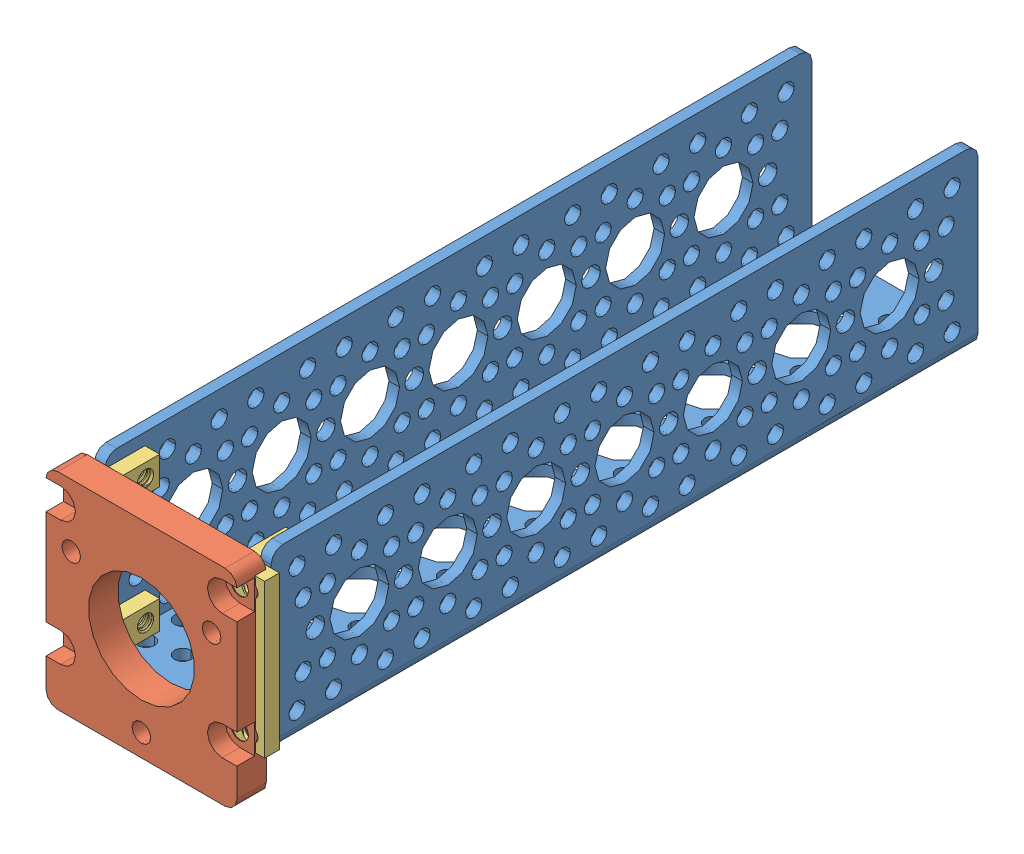
SolidWorks assembly Assem1, configuration Default. Lengths in mm.
Overall size (43.16 44.82 160.18).
4 component instances, 3 part files, 8 mates.
Components (placement in the parent):
- 6in Uchannel-1: 6in Uchannel [Default] at (-60.9804 -7.0848 -62.2029) size (38.1 38.1 152.4)
- L3v1 SlipRingBlock-1: L3v1 SlipRingBlock [Default] at (-43.0546 8.4219 91.6278) x (1 0 0) z (0 -1 0) size (41.15 6.35 44.45)
- J2v2 Angle Bracket 585508-1: J2v2 Angle Bracket 585508 [Default] at (-24.4044 11.9652 90.8328) x (0 1 0) z (1 0 0) size (33.02 12.43 7.88)
- J2v2 Angle Bracket 585508-2: J2v2 Angle Bracket 585508 [Default] at (-59.4564 11.9652 90.8328) x (0 -1 0) z (-1 0 0) size (33.02 12.43 7.88)
Mates (geometry in assembly coordinates):
- Coincident1: coincident anti-aligned: plane of 6in Uchannel-1 through (-25.1664 -4.7988 90.1971) normal (-1 0 0); plane of J2v2 Angle Bracket 585508-1 through (-25.1664 22.3945 81.5771) normal (1 0 0)
- Parallel1: parallel anti-aligned: plane of 6in Uchannel-1 through (-58.6944 -4.7988 90.1971) normal (0 1 0); plane of J2v2 Angle Bracket 585508-1 through (-20.4674 -4.5448 94.0078) normal (0 -1 0)
- Concentric1: concentric aligned: cylinder of 6in Uchannel-1 through (-22.8804 25.4356 84.6175) axis (1 0 0) radius 1.778; circle of J2v2 Angle Bracket 585508-1
- Coincident3: coincident anti-aligned: plane of 6in Uchannel-1 through (-58.6944 31.0152 90.1971) normal (1 0 0); plane of J2v2 Angle Bracket 585508-2 through (-58.6944 1.536 81.5771) normal (-1 0 0)
- Parallel2: parallel anti-aligned: plane of 6in Uchannel-1 through (-58.6944 -4.7988 90.1971) normal (0 1 0); plane of J2v2 Angle Bracket 585508-2 through (-63.3934 -4.5448 94.0078) normal (0 -1 0)
- Concentric2: concentric anti-aligned: cylinder of 6in Uchannel-1 through (-22.8804 25.4356 84.6175) axis (1 0 0) radius 1.778; cone of J2v2 Angle Bracket 585508-2 through (-55.5194 25.4356 84.6175) axis (-1 0 0)
- Parallel3: parallel anti-aligned: plane of L3v1 SlipRingBlock-1 through (-43.0546 8.4219 91.6278) normal (0 0 -1); plane of J2v2 Angle Bracket 585508-2 through (-59.4564 11.9652 94.0078) normal (0 0 1)
- Parallel4: parallel aligned: plane of 6in Uchannel-1 through (-60.9804 -7.0848 90.1971) normal (-1 0 0); plane of L3v1 SlipRingBlock-1 through (-63.6286 -13.8031 97.9778) normal (-1 0 0)
